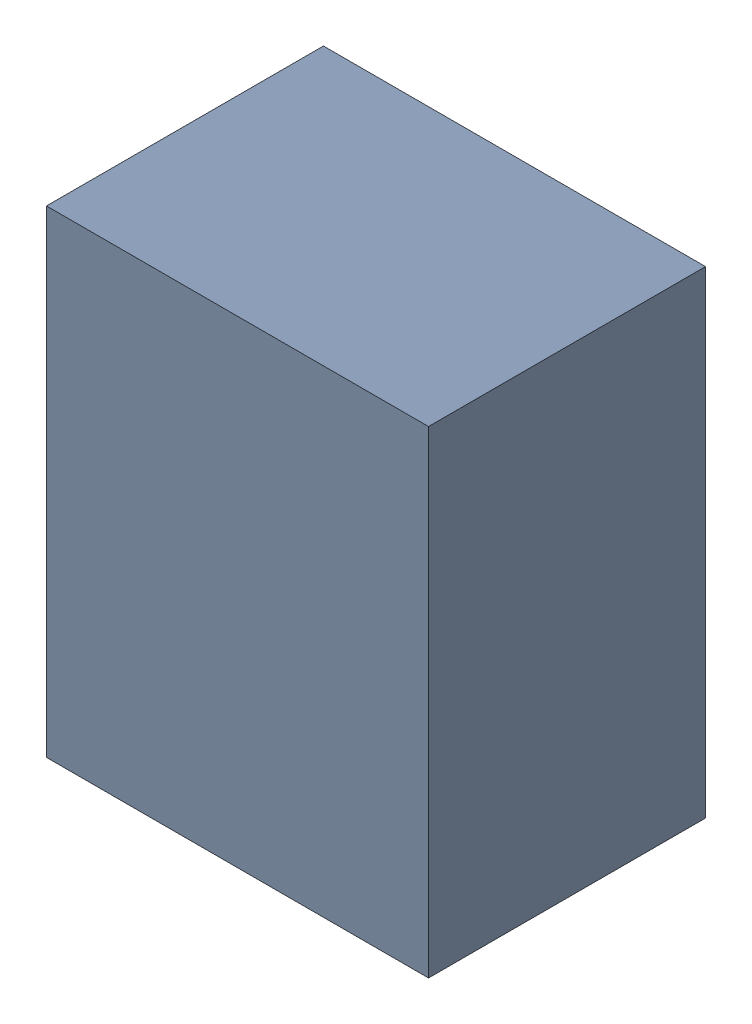
SolidWorks assembly U20, configuration Default. Lengths in mm.
Overall size (0.8 1 0.58).
2 component instances, 1 part files, 0 mates.
Components (placement in the parent):
- 836751984-1: 836751984 [Default] at (133.05 57 0.5) size (0.8 1 0.58)
  - Extruded_32-1: Extruded_32 [Default] at origin size (0.8 1 0.58)
